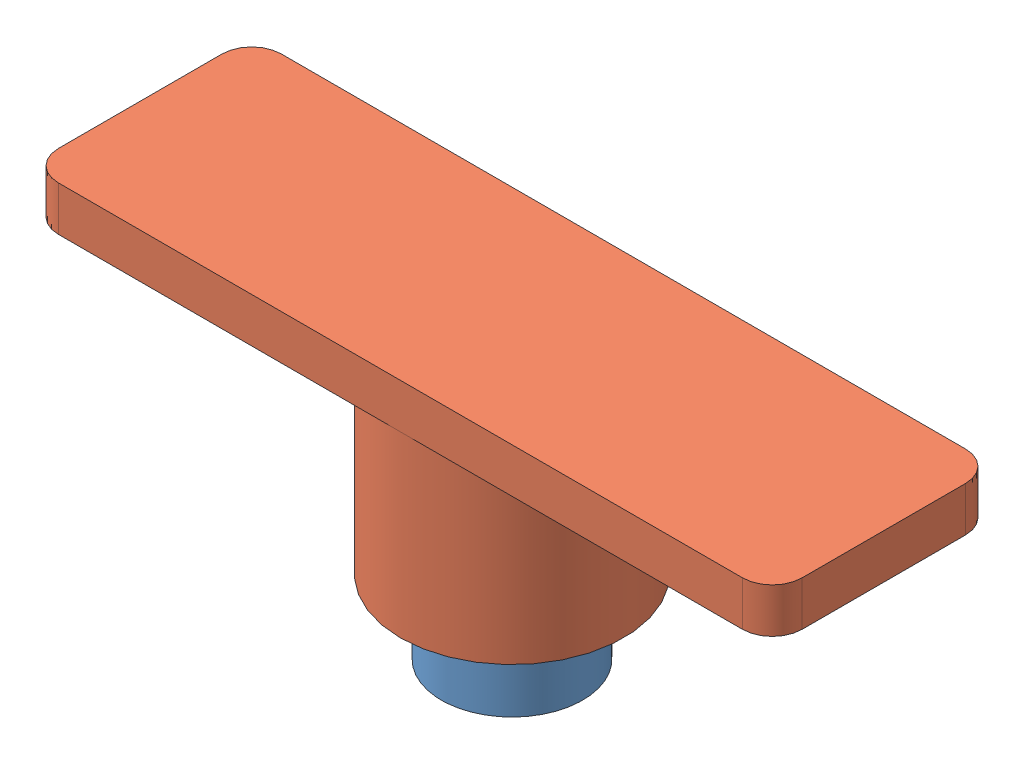
SolidWorks assembly Halterung, configuration Standard. Lengths in mm.
Overall size (50 20 15).
2 component instances, 2 part files, 3 mates.
Components (placement in the parent):
- Halterung-1: Halterung [Standard] at origin size (9.5 16 9.5)
- Halterung2-1: Halterung2 [Standard] at (0 20 0) x (-1 0 0) z (0 0 1) size (50 15 15)
Mates (geometry in assembly coordinates):
- Abstand1: distance = 20 mm anti-aligned: plane of Halterung2-1 through (0 20 0) normal (0 1 0); plane of Halterung-1 through (0 0 0) normal (0 -1 0)
- Konzentrisch1: concentric anti-aligned: cylinder of Halterung-1 through (0 16 0) axis (0 -1 0) radius 4.75; cylinder of Halterung2-1 through (0 5 0) axis (0 1 0) radius 7.5
- Deckungsgleich1: coincident aligned: plane of Halterung2-1 through (0 20 0) normal (0 0 1)
